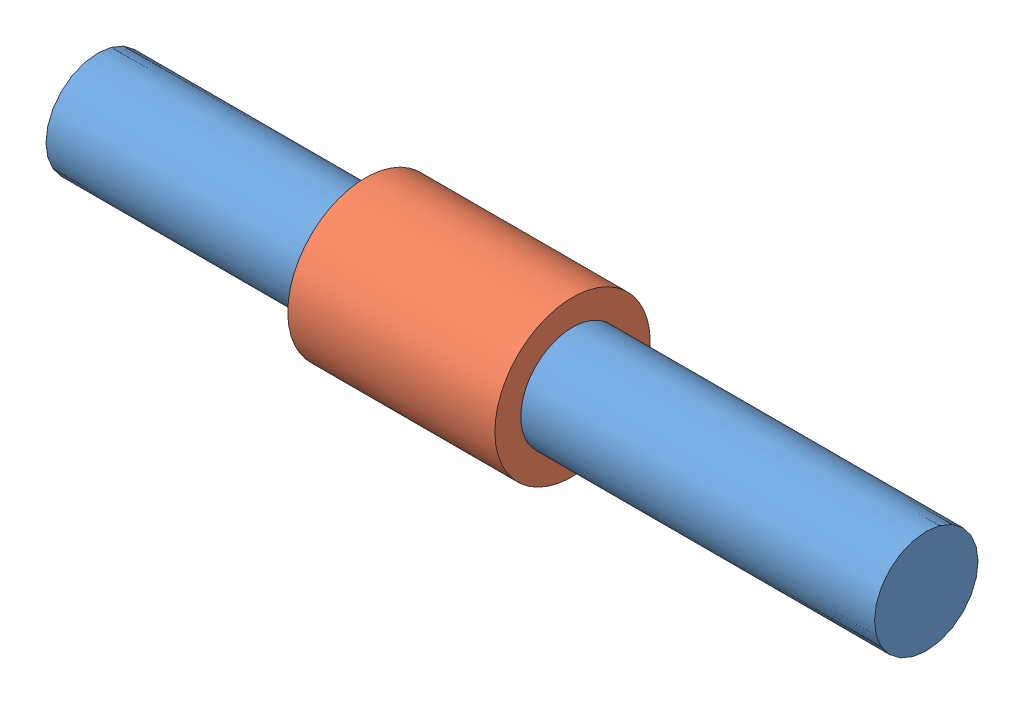
SolidWorks assembly Assem1, configuration Default. Lengths in mm.
Overall size (400 98.93 98.93).
2 component instances, 2 part files, 1 mates.
Components (placement in the parent):
- Shaft-1: Shaft [Default] at (-12.3284 -25.2981 23.6927) size (400 50 50)
- Bushing-1: Bushing [Default] at (-33.0906 -25.2981 23.6927) x (1 0 0) z (0 -0.404611 0.914489) size (100 75 75)
Mates (geometry in assembly coordinates):
- Concentric1: concentric aligned: cylinder of Shaft-1 through (187.6716 -25.2981 23.6927) axis (-1 0 0) radius 25; cylinder of Bushing-1 through (16.9094 -25.2981 23.6927) axis (-1 0 0) radius 25
